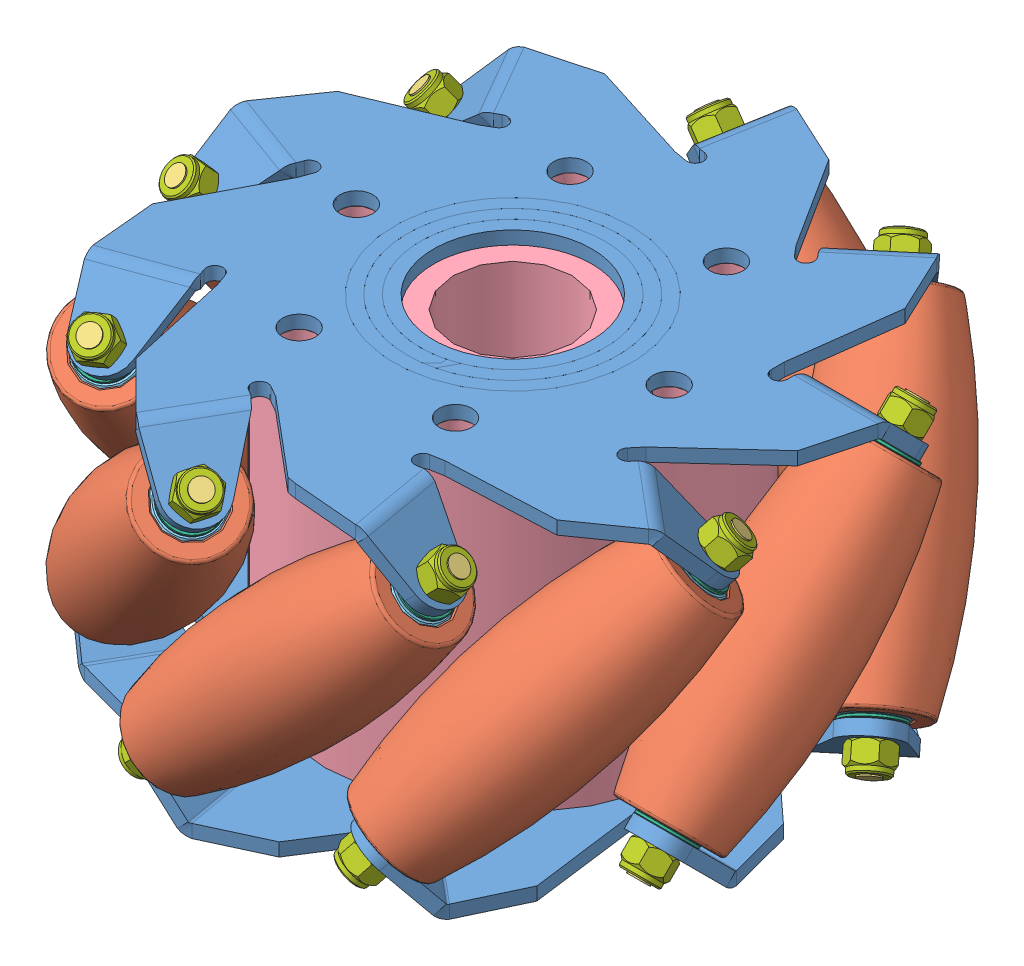
SolidWorks assembly 100mm Aluminum Mecanum wheels, configuration Default. Lengths in mm.
Overall size (142.96 50.22 143.44).
75 component instances, 7 part files, 0 mates.
Components (placement in the parent):
- BM6-1: BM6 [預設] at origin size (93.83 10.6 94.33)
- PRT0002-1: PRT0002 [預設] at origin size (46.81 47.08 51.59)
- PRT0002-2: PRT0002 [預設] x (0.766044 0 -0.642788) z (0.642788 0 0.766044) size (46.81 47.08 51.59)
- PRT0002-3: PRT0002 [預設] x (0.173648 0 -0.984808) z (0.984808 0 0.173648) size (46.81 47.08 51.59)
- PRT0002-4: PRT0002 [預設] x (-0.5 0 -0.866025) z (0.866025 0 -0.5) size (46.81 47.08 51.59)
- PRT0002-5: PRT0002 [預設] x (-0.939693 0 -0.34202) z (0.34202 0 -0.939693) size (46.81 47.08 51.59)
- PRT0002-6: PRT0002 [預設] x (-0.939693 0 0.34202) z (-0.34202 0 -0.939693) size (46.81 47.08 51.59)
- PRT0002-7: PRT0002 [預設] x (-0.5 0 0.866025) z (-0.866025 0 -0.5) size (46.81 47.08 51.59)
- PRT0002-8: PRT0002 [預設] x (0.173648 0 0.984808) z (-0.984808 0 0.173648) size (46.81 47.08 51.59)
- PRT0002-9: PRT0002 [預設] x (0.766044 0 0.642788) z (-0.642788 0 0.766044) size (46.81 47.08 51.59)
- BM6-2: BM6 [預設] at (0 45.8496 0) x (1 0 0) z (0 0 -1) size (93.83 10.6 94.33)
- BM1-1: BM1 [預設] at (40.2761 22.9248 -0.0045) x (0 -0.707107 -0.707107) z (1 0 0) size (4 60 4)
- BM1-2: BM1 [預設] at (30.8561 22.9248 25.8855) x (0.454519 -0.707107 -0.541675) z (0.766044 0 0.642788) size (4 60 4)
- BM1-3: BM1 [預設] at (6.9983 22.9248 39.6634) x (0.696364 -0.707107 -0.122788) z (0.173648 0 0.984808) size (4 60 4)
- BM1-4: BM1 [預設] at (-20.1341 22.9248 34.8823) x (0.612372 -0.707107 0.353553) z (-0.5 0 0.866025) size (4 60 4)
- BM1-5: BM1 [預設] at (-37.8456 22.9248 13.7794) x (0.241845 -0.707107 0.664463) z (-0.939693 0 0.34202) size (4 60 4)
- BM1-6: BM1 [預設] at (-37.8486 22.9248 -13.771) x (-0.241845 -0.707107 0.664463) z (-0.939693 0 -0.34202) size (4 60 4)
- BM1-7: BM1 [預設] at (-20.1419 22.9248 -34.8778) x (-0.612372 -0.707107 0.353553) z (-0.5 0 -0.866025) size (4 60 4)
- BM1-8: BM1 [預設] at (6.9894 22.9248 -39.665) x (-0.696364 -0.707107 -0.122788) z (0.173648 0 -0.984808) size (4 60 4)
- BM1-9: BM1 [預設] at (30.8504 22.9248 -25.8924) x (-0.454519 -0.707107 -0.541675) z (0.766044 0 -0.642788) size (4 60 4)
- BM4-1: BM4 [預設] at (0 0.0045 0.0045) size (57 46 57)
- BM7-1: BM7 [預設] at origin size (9.56 8.77 8.99)
- BM8-1: BM8 [預設] at origin size (7.84 5.87 6.18)
- BM7-2: BM7 [預設] x (0.766044 0 -0.642788) z (0.642788 0 0.766044) size (9.56 8.77 8.99)
- BM8-2: BM8 [預設] x (0.766044 0 -0.642788) z (0.642788 0 0.766044) size (7.84 5.87 6.18)
- BM7-3: BM7 [預設] x (0.173648 0 -0.984808) z (0.984808 0 0.173648) size (9.56 8.77 8.99)
- BM8-3: BM8 [預設] x (0.173648 0 -0.984808) z (0.984808 0 0.173648) size (7.84 5.87 6.18)
- BM7-4: BM7 [預設] x (-0.5 0 -0.866025) z (0.866025 0 -0.5) size (9.56 8.77 8.99)
- BM8-4: BM8 [預設] x (-0.5 0 -0.866025) z (0.866025 0 -0.5) size (7.84 5.87 6.18)
- BM7-5: BM7 [預設] x (-0.939693 0 -0.34202) z (0.34202 0 -0.939693) size (9.56 8.77 8.99)
- BM8-5: BM8 [預設] x (-0.939693 0 -0.34202) z (0.34202 0 -0.939693) size (7.84 5.87 6.18)
- BM7-6: BM7 [預設] x (-0.939693 0 0.34202) z (-0.34202 0 -0.939693) size (9.56 8.77 8.99)
- BM8-6: BM8 [預設] x (-0.939693 0 0.34202) z (-0.34202 0 -0.939693) size (7.84 5.87 6.18)
- BM7-7: BM7 [預設] x (-0.5 0 0.866025) z (-0.866025 0 -0.5) size (9.56 8.77 8.99)
- BM8-7: BM8 [預設] x (-0.5 0 0.866025) z (-0.866025 0 -0.5) size (7.84 5.87 6.18)
- BM7-8: BM7 [預設] x (0.173648 0 0.984808) z (-0.984808 0 0.173648) size (9.56 8.77 8.99)
- BM8-8: BM8 [預設] x (0.173648 0 0.984808) z (-0.984808 0 0.173648) size (7.84 5.87 6.18)
- BM7-9: BM7 [預設] x (0.766044 0 0.642788) z (-0.642788 0 0.766044) size (9.56 8.77 8.99)
- BM8-9: BM8 [預設] x (0.766044 0 0.642788) z (-0.642788 0 0.766044) size (7.84 5.87 6.18)
- BM7-10: BM7 [預設] at (0 45.8496 0) x (1 0 0) z (0 0 -1) size (9.56 8.77 8.99)
- BM8-10: BM8 [預設] at (0 45.8496 0) x (1 0 0) z (0 0 -1) size (7.84 5.87 6.18)
- BM7-11: BM7 [預設] at (0 45.8496 0) x (0.766044 0 0.642788) z (0.642788 0 -0.766044) size (9.56 8.77 8.99)
- BM8-11: BM8 [預設] at (0 45.8496 0) x (0.766044 0 0.642788) z (0.642788 0 -0.766044) size (7.84 5.87 6.18)
- BM7-12: BM7 [預設] at (0 45.8496 0) x (0.173648 0 0.984808) z (0.984808 0 -0.173648) size (9.56 8.77 8.99)
- BM8-12: BM8 [預設] at (0 45.8496 0) x (0.173648 0 0.984808) z (0.984808 0 -0.173648) size (7.84 5.87 6.18)
- BM7-13: BM7 [預設] at (0 45.8496 0) x (-0.5 0 0.866025) z (0.866025 0 0.5) size (9.56 8.77 8.99)
- BM8-13: BM8 [預設] at (0 45.8496 0) x (-0.5 0 0.866025) z (0.866025 0 0.5) size (7.84 5.87 6.18)
- BM7-14: BM7 [預設] at (0 45.8496 0) x (-0.939693 0 0.34202) z (0.34202 0 0.939693) size (9.56 8.77 8.99)
- BM8-14: BM8 [預設] at (0 45.8496 0) x (-0.939693 0 0.34202) z (0.34202 0 0.939693) size (7.84 5.87 6.18)
- BM7-15: BM7 [預設] at (0 45.8496 0) x (-0.939693 0 -0.34202) z (-0.34202 0 0.939693) size (9.56 8.77 8.99)
- BM8-15: BM8 [預設] at (0 45.8496 0) x (-0.939693 0 -0.34202) z (-0.34202 0 0.939693) size (7.84 5.87 6.18)
- BM7-16: BM7 [預設] at (0 45.8496 0) x (-0.5 0 -0.866025) z (-0.866025 0 0.5) size (9.56 8.77 8.99)
- BM8-16: BM8 [預設] at (0 45.8496 0) x (-0.5 0 -0.866025) z (-0.866025 0 0.5) size (7.84 5.87 6.18)
- BM7-17: BM7 [預設] at (0 45.8496 0) x (0.173648 0 -0.984808) z (-0.984808 0 -0.173648) size (9.56 8.77 8.99)
- BM8-17: BM8 [預設] at (0 45.8496 0) x (0.173648 0 -0.984808) z (-0.984808 0 -0.173648) size (7.84 5.87 6.18)
- BM7-18: BM7 [預設] at (0 45.8496 0) x (0.766044 0 -0.642788) z (-0.642788 0 -0.766044) size (9.56 8.77 8.99)
- BM8-18: BM8 [預設] at (0 45.8496 0) x (0.766044 0 -0.642788) z (-0.642788 0 -0.766044) size (7.84 5.87 6.18)
- BM9-1: BM9 [預設] at origin size (6.82 6.58 6.89)
- BM9-2: BM9 [預設] x (0.766044 0 -0.642788) z (0.642788 0 0.766044) size (6.82 6.58 6.89)
- BM9-3: BM9 [預設] x (0.173648 0 -0.984808) z (0.984808 0 0.173648) size (6.82 6.58 6.89)
- BM9-4: BM9 [預設] x (-0.5 0 -0.866025) z (0.866025 0 -0.5) size (6.82 6.58 6.89)
- BM9-5: BM9 [預設] x (-0.939693 0 -0.34202) z (0.34202 0 -0.939693) size (6.82 6.58 6.89)
- BM9-6: BM9 [預設] x (-0.939693 0 0.34202) z (-0.34202 0 -0.939693) size (6.82 6.58 6.89)
- BM9-7: BM9 [預設] x (-0.5 0 0.866025) z (-0.866025 0 -0.5) size (6.82 6.58 6.89)
- BM9-8: BM9 [預設] x (0.173648 0 0.984808) z (-0.984808 0 0.173648) size (6.82 6.58 6.89)
- BM9-9: BM9 [預設] x (0.766044 0 0.642788) z (-0.642788 0 0.766044) size (6.82 6.58 6.89)
- BM9-10: BM9 [預設] at (0 45.8496 0) x (1 0 0) z (0 0 -1) size (6.82 6.58 6.89)
- BM9-11: BM9 [預設] at (0 45.8496 0) x (0.766044 0 0.642788) z (0.642788 0 -0.766044) size (6.82 6.58 6.89)
- BM9-12: BM9 [預設] at (0 45.8496 0) x (0.173648 0 0.984808) z (0.984808 0 -0.173648) size (6.82 6.58 6.89)
- BM9-13: BM9 [預設] at (0 45.8496 0) x (-0.5 0 0.866025) z (0.866025 0 0.5) size (6.82 6.58 6.89)
- BM9-14: BM9 [預設] at (0 45.8496 0) x (-0.939693 0 0.34202) z (0.34202 0 0.939693) size (6.82 6.58 6.89)
- BM9-15: BM9 [預設] at (0 45.8496 0) x (-0.939693 0 -0.34202) z (-0.34202 0 0.939693) size (6.82 6.58 6.89)
- BM9-16: BM9 [預設] at (0 45.8496 0) x (-0.5 0 -0.866025) z (-0.866025 0 0.5) size (6.82 6.58 6.89)
- BM9-17: BM9 [預設] at (0 45.8496 0) x (0.173648 0 -0.984808) z (-0.984808 0 -0.173648) size (6.82 6.58 6.89)
- BM9-18: BM9 [預設] at (0 45.8496 0) x (0.766044 0 -0.642788) z (-0.642788 0 -0.766044) size (6.82 6.58 6.89)
